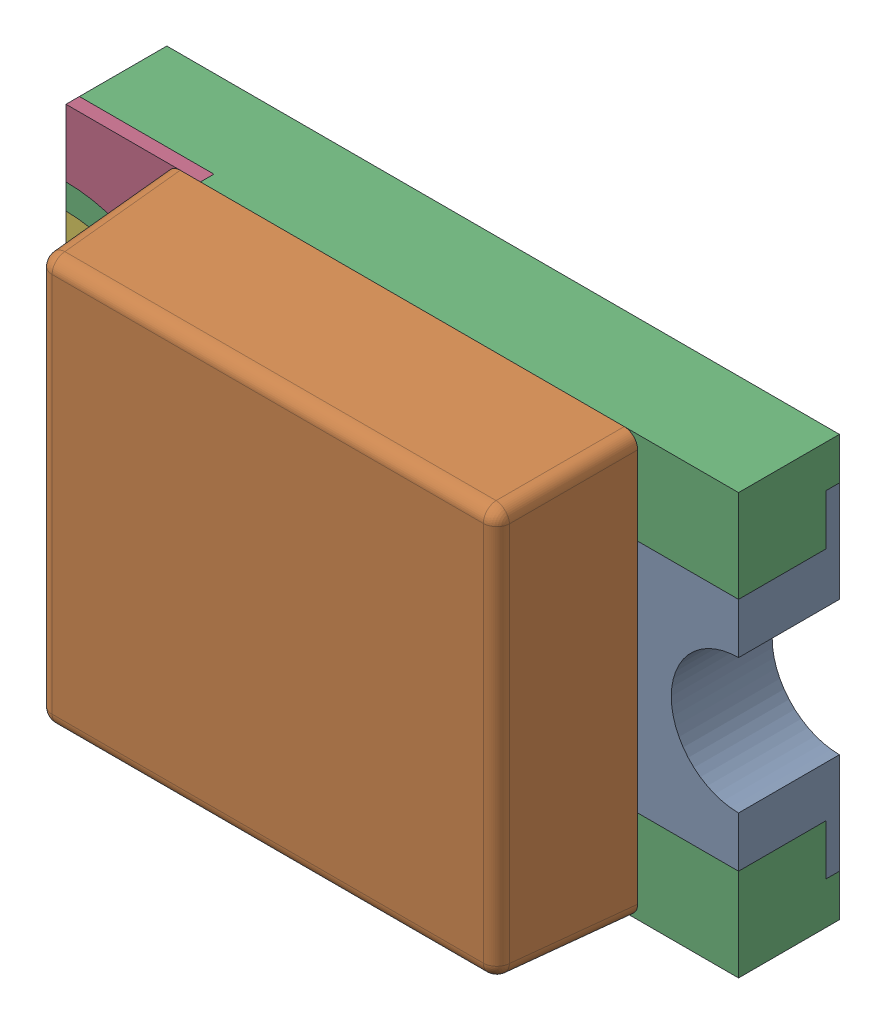
SolidWorks assembly GREEN, configuration Default. Lengths in mm.
Overall size (2 1.25 0.7).
6 component instances, 5 part files, 0 mates.
Components (placement in the parent):
- base-1: base [Default] at (0.8 0 0) x (-1 0 0) z (0 0 1) size (0.4 1 0.3)
- cover-1: cover [Default] at (0 0 0.3) size (1.4 1.25 0.4)
- housing-1: housing [Default] at origin size (2 1.25 0.3)
- marking-1: marking [Default] at (-0.8 0.525 0.26) size (0.4 0.48 0.04)
- marking-2: marking [Default] at (-0.8 -0.525 0.3) x (1 0 0) z (0 0 -1) size (0.4 0.48 0.04)
- base_2-1: base_2 [Default] at (-0.8 0 0) size (0.4 1 0.3)
